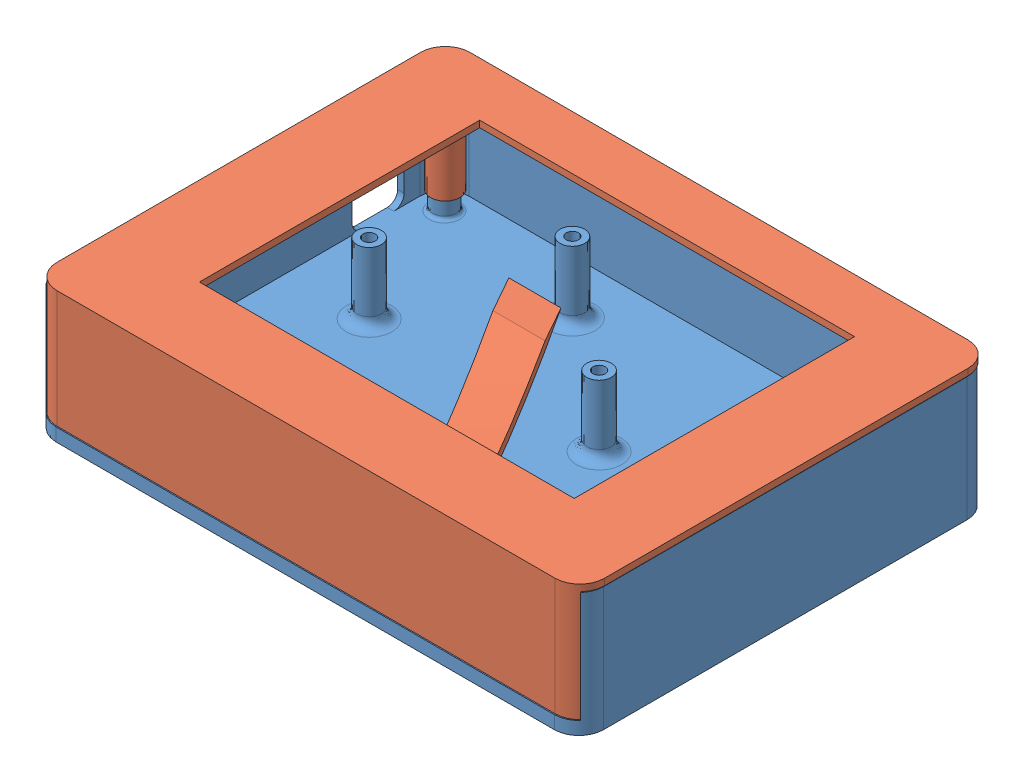
SolidWorks assembly eink_assembly, configuration Default. Lengths in mm.
Overall size (133.32 31.81 100.76).
2 component instances, 2 part files, 0 mates.
Components (placement in the parent):
- eink_controller_case_back_test-2: eink_controller_case_back_test [Default] at (56.9635 46.3943 104.1175) size (133.3 30.16 100.54)
- eink_controller_case_front_test2-2: eink_controller_case_front_test2 [Default] at (57.2321 76.6165 100.8811) x (-1 0 0) z (0 0 1) size (133.3 28.57 100.54)
